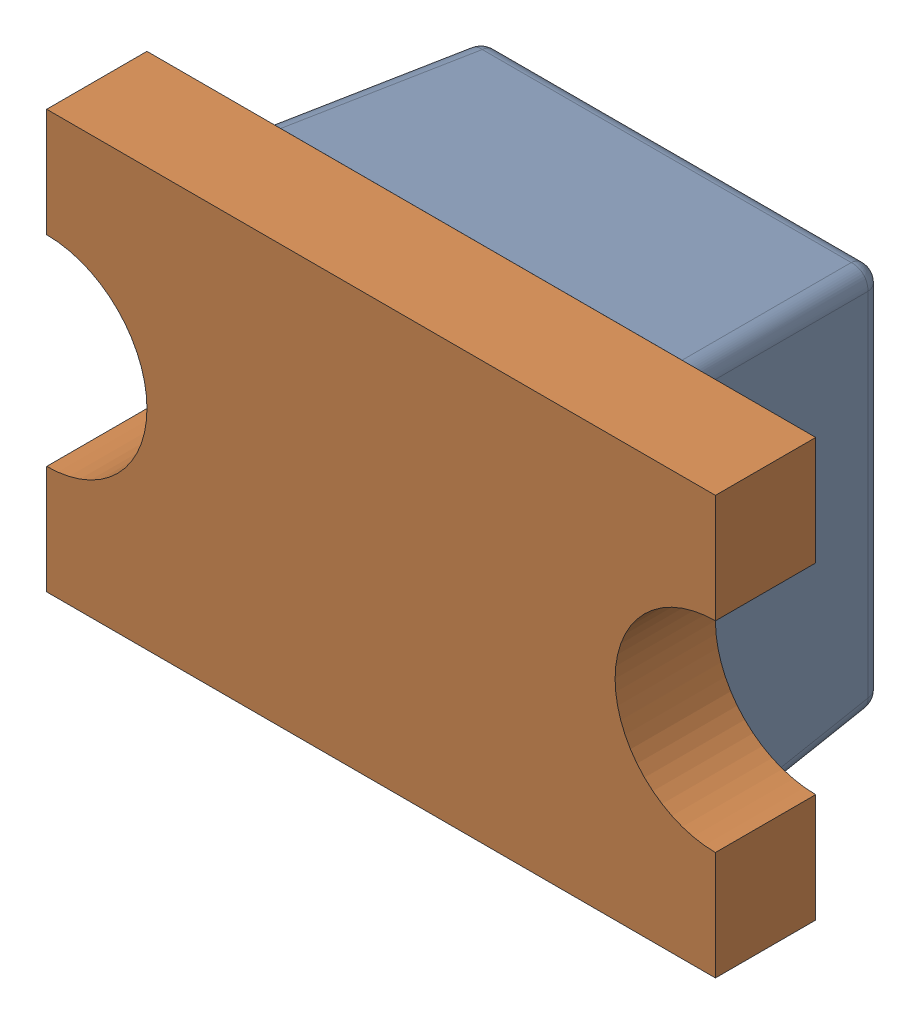
SolidWorks assembly D9_1, configuration Default. Lengths in mm.
Overall size (2 1.25 0.9).
2 component instances, 2 part files, 0 mates.
Components (placement in the parent):
- LED 0805 Lens RED-1: LED 0805 Lens RED [Default] at (81.7879 95.758 -1.2114) x (-1 0 0) z (0 -1 0) size (1.3 0.6 1.25)
- LED 0805 Base RED-1: LED 0805 Base RED [Default] at (81.7879 95.758 -1.2114) x (-1 0 0) z (0 -1 0) size (2 0.4 1.25)
